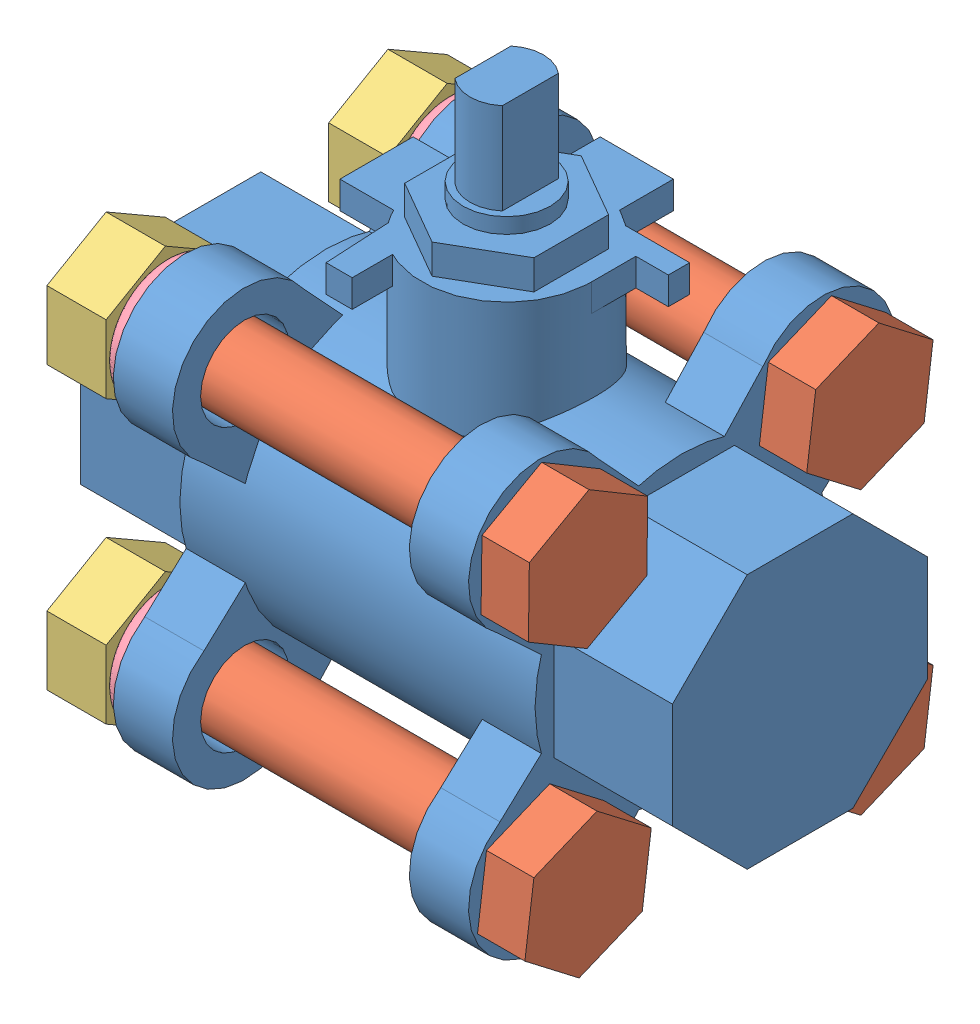
SolidWorks assembly Sharpe 39036 asm Valve Only, configuration Default. Lengths in mm.
Overall size (63.5 64.95 48.93).
13 component instances, 4 part files, 39 mates.
Components (placement in the parent):
- Sharpe 39036-1: Sharpe 39036 [Default] at (-14.0964 -12.8458 82.9356) size (63.5 64.02 45.72)
- Sharpe 39036 Bolt-1: Sharpe 39036 Bolt [Default] at (29.0836 2.2672 98.0486) x (-1 0 0) z (0 -0.872825 -0.488034) size (53.34 14.66 12.7)
- Sharpe 39036 nut-1: Sharpe 39036 nut [Default] at (-22.6054 2.2672 98.0486) size (6.35 14.66 12.7)
- Sharpe 39036 washer-2: Sharpe 39036 washer [Default] at (-16.2554 2.2672 98.0486) size (2.16 13.21 13.21)
- Sharpe 39036 washer-3: Sharpe 39036 washer [Default] at (-16.2554 2.2672 67.8226) size (2.16 13.21 13.21)
- Sharpe 39036 nut-2: Sharpe 39036 nut [Default] at (-22.6054 -27.9588 98.0486) size (6.35 14.66 12.7)
- Sharpe 39036 Bolt-2: Sharpe 39036 Bolt [Default] at (29.0836 -27.9588 98.0486) x (-1 0 0) z (0 -0.924225 -0.381849) size (53.34 14.66 12.7)
- Sharpe 39036 Bolt-3: Sharpe 39036 Bolt [Default] at (29.0836 2.2672 67.8226) x (-1 0 0) z (0 -0.924225 -0.381849) size (53.34 14.66 12.7)
- Sharpe 39036 Bolt-4: Sharpe 39036 Bolt [Default] at (29.0836 -27.9588 67.8226) x (-1 0 0) z (0 -0.924225 -0.381849) size (53.34 14.66 12.7)
- Sharpe 39036 nut-3: Sharpe 39036 nut [Default] at (-22.6054 2.2672 67.8226) size (6.35 14.66 12.7)
- Sharpe 39036 nut-4: Sharpe 39036 nut [Default] at (-22.6054 -27.9588 67.8226) size (6.35 14.66 12.7)
- Sharpe 39036 washer-4: Sharpe 39036 washer [Default] at (-16.2554 -27.9588 67.8226) size (2.16 13.21 13.21)
- Sharpe 39036 washer-5: Sharpe 39036 washer [Default] at (-16.2554 -27.9588 98.0486) size (2.16 13.21 13.21)
Mates (geometry in assembly coordinates):
- Coincident5: coincident anti-aligned: plane of Sharpe 39036-1 through (24.0036 -12.8458 82.9356) normal (1 0 0); plane of Sharpe 39036 Bolt-1 through (24.0036 2.2672 98.0486) normal (-1 0 0)
- Concentric4: concentric anti-aligned: cylinder of Sharpe 39036-1 through (24.0036 2.2672 98.0486) axis (-1 0 0) radius 4.7307; cylinder of Sharpe 39036 Bolt-1 through (-24.2564 2.2672 98.0486) axis (1 0 0) radius 3.9688
- Coincident6: coincident anti-aligned: plane of Sharpe 39036-1 through (-14.0964 -12.8458 82.9356) normal (-1 0 0); plane of Sharpe 39036 washer-2 through (-14.0964 2.2672 98.0486) normal (1 0 0)
- Coincident7: coincident aligned: cylinder of Sharpe 39036 Bolt-1 through (-24.2564 2.2672 98.0486) axis (1 0 0) radius 3.9688; circle of Sharpe 39036 washer-2
- Coincident8: coincident anti-aligned: plane of Sharpe 39036 nut-1 through (-16.2554 2.2672 98.0486) normal (1 0 0); plane of Sharpe 39036 washer-2 through (-16.2554 2.2672 98.0486) normal (-1 0 0)
- Concentric5: concentric anti-aligned: cylinder of Sharpe 39036 Bolt-1 through (-24.2564 2.2672 98.0486) axis (1 0 0) radius 3.9688; cylinder of Sharpe 39036 nut-1 through (-16.2554 2.2672 98.0486) axis (-1 0 0) radius 3.9688
- Coincident9: coincident anti-aligned: plane of Sharpe 39036-1 through (24.0036 -12.8458 82.9356) normal (1 0 0); plane of Sharpe 39036 Bolt-2 through (24.0036 -27.9588 98.0486) normal (-1 0 0)
- Concentric6: concentric anti-aligned: cylinder of Sharpe 39036-1 through (24.0036 -27.9588 98.0486) axis (-1 0 0) radius 4.7307; cylinder of Sharpe 39036 Bolt-2 through (-24.2564 -27.9588 98.0486) axis (1 0 0) radius 3.9688
- Coincident10: coincident anti-aligned: plane of Sharpe 39036-1 through (-14.0964 -12.8458 82.9356) normal (-1 0 0); plane of Sharpe 39036 washer-5 through (-14.0964 -27.9588 98.0486) normal (1 0 0)
- Concentric7: concentric anti-aligned: cylinder of Sharpe 39036 Bolt-2 through (-24.2564 -27.9588 98.0486) axis (1 0 0) radius 3.9688; cylinder of Sharpe 39036 washer-5 through (-14.0964 -27.9588 98.0486) axis (-1 0 0) radius 3.9688
- Coincident11: coincident anti-aligned: plane of Sharpe 39036 nut-2 through (-16.2554 -27.9588 98.0486) normal (1 0 0); circle of Sharpe 39036 washer-5
- Concentric8: concentric anti-aligned: cylinder of Sharpe 39036 nut-2 through (-16.2554 -27.9588 98.0486) axis (-1 0 0) radius 3.9688; cylinder of Sharpe 39036 Bolt-2 through (-24.2564 -27.9588 98.0486) axis (1 0 0) radius 3.9688
- Coincident12: coincident anti-aligned: plane of Sharpe 39036-1 through (24.0036 -12.8458 82.9356) normal (1 0 0); plane of Sharpe 39036 Bolt-3 through (24.0036 2.2672 67.8226) normal (-1 0 0)
- Concentric9: concentric anti-aligned: cylinder of Sharpe 39036-1 through (24.0036 2.2672 67.8226) axis (-1 0 0) radius 4.7307; cylinder of Sharpe 39036 Bolt-3 through (-24.2564 2.2672 67.8226) axis (1 0 0) radius 3.9688
- Coincident13: coincident anti-aligned: plane of Sharpe 39036-1 through (24.0036 -12.8458 82.9356) normal (1 0 0); plane of Sharpe 39036 Bolt-4 through (24.0036 -27.9588 67.8226) normal (-1 0 0)
- Concentric10: concentric anti-aligned: cylinder of Sharpe 39036-1 through (24.0036 -27.9588 67.8226) axis (-1 0 0) radius 4.7307; cylinder of Sharpe 39036 Bolt-4 through (-24.2564 -27.9588 67.8226) axis (1 0 0) radius 3.9688
- Coincident14: coincident anti-aligned: plane of Sharpe 39036-1 through (-14.0964 -12.8458 82.9356) normal (-1 0 0); plane of Sharpe 39036 washer-3 through (-14.0964 2.2672 67.8226) normal (1 0 0)
- Concentric11: concentric anti-aligned: cylinder of Sharpe 39036 washer-3 through (-14.0964 2.2672 67.8226) axis (-1 0 0) radius 3.9688; cylinder of Sharpe 39036 Bolt-3 through (-24.2564 2.2672 67.8226) axis (1 0 0) radius 3.9688
- Coincident15: coincident anti-aligned: plane of Sharpe 39036-1 through (-14.0964 -12.8458 82.9356) normal (-1 0 0); plane of Sharpe 39036 washer-4 through (-14.0964 -27.9588 67.8226) normal (1 0 0)
- Concentric12: concentric anti-aligned: cylinder of Sharpe 39036 Bolt-4 through (-24.2564 -27.9588 67.8226) axis (1 0 0) radius 3.9688; cylinder of Sharpe 39036 washer-4 through (-14.0964 -27.9588 67.8226) axis (-1 0 0) radius 3.9688
- Coincident16: coincident anti-aligned: plane of Sharpe 39036 washer-3 through (-16.2554 2.2672 67.8226) normal (-1 0 0); plane of Sharpe 39036 nut-3 through (-16.2554 2.2672 67.8226) normal (1 0 0)
- Concentric13: concentric anti-aligned: cylinder of Sharpe 39036 Bolt-3 through (-24.2564 2.2672 67.8226) axis (1 0 0) radius 3.9688; cylinder of Sharpe 39036 nut-3 through (-16.2554 2.2672 67.8226) axis (-1 0 0) radius 3.9688
- Coincident17: coincident anti-aligned: plane of Sharpe 39036 nut-4 through (-16.2554 -27.9588 67.8226) normal (1 0 0); plane of Sharpe 39036 washer-4 through (-16.2554 -27.9588 67.8226) normal (-1 0 0)
- Coincident18: coincident aligned: cylinder of Sharpe 39036 Bolt-4 through (-24.2564 -27.9588 67.8226) axis (1 0 0) radius 3.9688; circle of Sharpe 39036 nut-4
- Coincident19: coincident anti-aligned: plane of Sharpe 39036-1 through (4.9536 18.539 82.6516) normal (0 1 0); plane of ? through (4.9536 18.539 82.6516) normal (0 -1 0)
- Coincident23: coincident anti-aligned: plane of ? through (4.9536 23.619 82.6516) normal (0 1 0); plane of ? through (-1.6233 23.619 79.01) normal (0 -1 0)
- Concentric17: concentric anti-aligned: cylinder of ? through (19.9641 23.619 82.4832) axis (0 -1 0) radius 1.2446; cylinder of ? through (19.9641 31.4581 82.4832) axis (0 1 0) radius 1.2446
- Concentric20: concentric anti-aligned: cylinder of ? through (4.9536 38.0367 82.6516) axis (0 -1 0) radius 4.1656; cylinder of ? through (4.9536 39.2051 82.6516) axis (0 1 0) radius 9.7155
- Concentric23: concentric anti-aligned: cylinder of ? through (-10.0568 23.619 82.82) axis (0 -1 0) radius 1.2446; cylinder of ? through (-10.0568 31.4581 82.82) axis (0 1 0) radius 1.2446
- Concentric24: concentric anti-aligned: cylinder of ? through (19.9641 23.619 82.4832) axis (0 -1 0) radius 1.2446; cylinder of ? through (19.9641 31.4581 82.4832) axis (0 1 0) radius 1.2446
- Coincident29: coincident anti-aligned: plane of ? through (-1.6233 30.3659 79.01) normal (0 1 0); plane of ? through (4.9536 30.3659 82.6516) normal (0 -1 0)
- Parallel4: parallel anti-aligned: plane of ? through (-1.6233 30.3659 79.01) normal (0 1 0); plane of ? through (34.9745 31.4581 82.3148) normal (0 -1 0)
- Parallel6: parallel aligned: plane of Sharpe 39036-1 through (36.7036 -12.8458 82.9356) normal (1 0 0); plane of ? through (19.4951 93.3833 68.1101) normal (1 0 0)
- Concentric28: concentric anti-aligned: cylinder of Sharpe 39036-1 through (4.9536 18.539 82.6516) axis (0 -1 0) radius 4.6736; cylinder of ? through (4.9536 30.3659 82.6516) axis (0 1 0) radius 4.1656
- Coincident30: coincident anti-aligned: plane of ? through (4.9536 32.9821 82.6516) normal (0 1 0); plane of ? through (27.5723 32.9821 97.1931) normal (0 -1 0)
- Concentric37: concentric anti-aligned: cylinder of Sharpe 39036 Bolt-2 through (-24.2564 -27.9588 98.0486) axis (1 0 0) radius 3.9688; cylinder of ? through (36.9576 -27.9588 98.0486) axis (-1 0 0) radius 4.1275
- Coincident31: coincident: plane of ? through (36.9576 56.5597 108.9071) normal (1 0 0); plane of ? through (36.9576 56.5597 55.8211) normal (1 0 0)
- Coincident32: coincident: plane of ? through (-39.2424 56.5597 108.9071) normal (0 1 0); plane of ? through (-39.2424 56.5597 55.8211) normal (0 1 0)
- Coincident33: coincident anti-aligned: plane of ? through (36.9576 -45.0403 82.3641) normal (0 0 -1); plane of ? through (36.9576 -45.0403 82.3641) normal (0 0 1)
